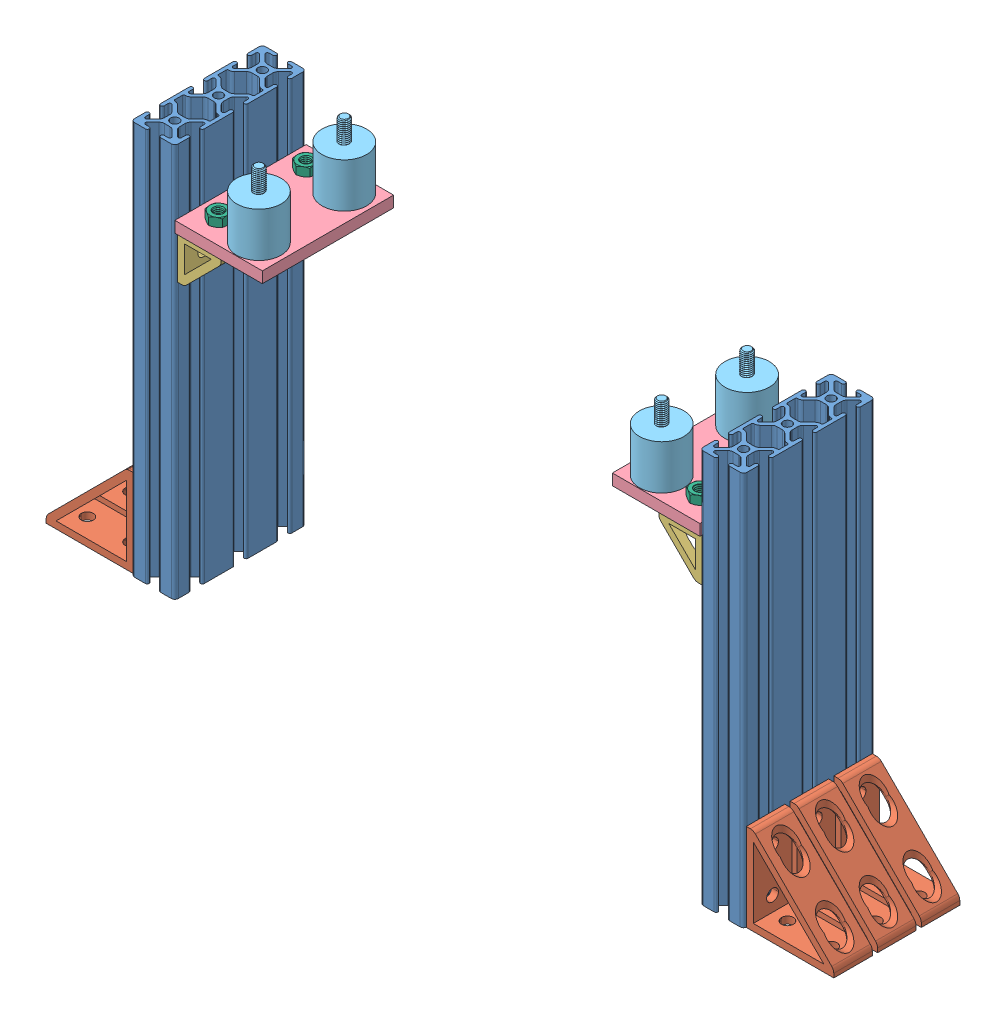
SolidWorks assembly 1, configuration Default. Lengths in mm.
Overall size (450 226.59 75).
32 component instances, 7 part files, 85 mates.
Components (placement in the parent):
- Some Part-2: Some Part [Default] at (-162.5 0 0) x (1 0 0) z (0 -1 0) size (25 75 225)
- Some Part-3: Some Part [Default] at (162.5 0 0) x (1 0 0) z (0 -1 0) size (25 75 225)
- 25_4136-1: 25_4136 [Default] at (-175 0 0) x (0 0 1) z (-1 0 0) size (22 50 50)
- 25_4136-2: 25_4136 [Default] at (175 0 -25) x (0 0 -1) z (1 0 0) size (22 50 50)
- 25_4136-3: 25_4136 [Default] at (175 0 25) x (0 0 -1) z (1 0 0) size (22 50 50)
- 25_4136-4: 25_4136 [Default] at (-175 0 -25) x (0 0 1) z (-1 0 0) size (22 50 50)
- 25_4136-5: 25_4136 [Default] at (175 0 0) x (0 0 -1) z (1 0 0) size (22 50 50)
- 25_4136-6: 25_4136 [Default] at (-175 0 25) x (0 0 1) z (-1 0 0) size (22 50 50)
- 25_4132-1: 25_4132 [Default] at (-150 181.787 25) x (0 0 -1) z (0 -1 0) size (22 25 25)
- 25_4132-2: 25_4132 [Default] at (-150 181.787 -25) x (0 0 -1) z (0 -1 0) size (22 25 25)
- 25_4132-3: 25_4132 [Default] at (-150 181.787 0) x (0 0 1) z (1 0 0) size (22 25 25)
- 25_4132-4: 25_4132 [Default] at (150 181.787 0) x (0 0 -1) z (-1 0 0) size (22 25 25)
- 25_4132-5: 25_4132 [Default] at (150 181.787 25) x (0 0 -1) z (-1 0 0) size (22 25 25)
- 25_4132-6: 25_4132 [Default] at (150 181.787 -25) x (0 0 -1) z (-1 0 0) size (22 25 25)
- Mounting Block-1: Mounting Block [Default] at (-125 188.137 0) x (1 0 0) z (0 -1 0) size (50 75 6.35)
- Mounting Block-2: Mounting Block [Default] at (125 188.137 0) x (-1 0 0) z (0 -1 0) size (50 75 6.35)
- 9225K67_Vibration-Damping Sandwich Mount with Studs-1: 9225K67_Vibration-Damping Sandwich Mount with Studs [9225K67] at (115.071 200.837 -24.4) size (25.4 51.51 25.4)
- 9225K67_Vibration-Damping Sandwich Mount with Studs-2: 9225K67_Vibration-Damping Sandwich Mount with Studs [9225K67] at (-115.071 200.837 24.4) size (25.4 51.51 25.4)
- 9225K67_Vibration-Damping Sandwich Mount with Studs-3: 9225K67_Vibration-Damping Sandwich Mount with Studs [9225K67] at (115.071 200.837 24.4) size (25.4 51.51 25.4)
- 9225K67_Vibration-Damping Sandwich Mount with Studs-4: 9225K67_Vibration-Damping Sandwich Mount with Studs [9225K67] at (-115.071 200.837 -24.4) size (25.4 51.51 25.4)
- 91828A251_18-8 Stainless Steel Hex Nut-1: 91828A251_18-8 Stainless Steel Hex Nut [91828A251] at (115.071 179.287 -24.4) x (1 0 0) z (0 -1 0) size (10 11.55 5.57)
- 94500A314_316 Stainless Steel Button Head Hex Drive Screws-1: 94500A314_316 Stainless Steel Button Head Hex Drive Screws [94500A314] at (137.5 174.487 -25) x (1 0 0) z (0 -1 0) size (10.5 10.5 13.87)
- 91828A251_18-8 Stainless Steel Hex Nut-2: 91828A251_18-8 Stainless Steel Hex Nut [91828A251] at (115.071 179.287 24.4) x (1 0 0) z (0 -1 0) size (10 11.55 5.57)
- 91828A251_18-8 Stainless Steel Hex Nut-3: 91828A251_18-8 Stainless Steel Hex Nut [91828A251] at (-115.071 179.287 -24.4) x (0.837169 0 0.546944) z (0 -1 0) size (10 11.55 5.57)
- 91828A251_18-8 Stainless Steel Hex Nut-4: 91828A251_18-8 Stainless Steel Hex Nut [91828A251] at (137.5 190.637 -25) x (1 0 0) z (0 1 0) size (10 11.55 5.57)
- 91828A251_18-8 Stainless Steel Hex Nut-5: 91828A251_18-8 Stainless Steel Hex Nut [91828A251] at (137.5 190.637 25) x (1 0 0) z (0 -1 0) size (10 11.55 5.57)
- 91828A251_18-8 Stainless Steel Hex Nut-6: 91828A251_18-8 Stainless Steel Hex Nut [91828A251] at (-137.5 190.637 -25) x (1 0 0) z (0 1 0) size (10 11.55 5.57)
- 91828A251_18-8 Stainless Steel Hex Nut-7: 91828A251_18-8 Stainless Steel Hex Nut [91828A251] at (-115.071 179.287 24.4) x (0.837169 0 0.546944) z (0 -1 0) size (10 11.55 5.57)
- 91828A251_18-8 Stainless Steel Hex Nut-8: 91828A251_18-8 Stainless Steel Hex Nut [91828A251] at (-137.5 190.637 25) x (1 0 0) z (0 1 0) size (10 11.55 5.57)
- 94500A314_316 Stainless Steel Button Head Hex Drive Screws-2: 94500A314_316 Stainless Steel Button Head Hex Drive Screws [94500A314] at (137.5 174.487 25) x (1 0 0) z (0 -1 0) size (10.5 10.5 13.87)
- 94500A314_316 Stainless Steel Button Head Hex Drive Screws-3: 94500A314_316 Stainless Steel Button Head Hex Drive Screws [94500A314] at (-137.5 174.487 -25) x (0.731174 0 0.682191) z (0 -1 0) size (10.5 10.5 13.87)
- 94500A314_316 Stainless Steel Button Head Hex Drive Screws-4: 94500A314_316 Stainless Steel Button Head Hex Drive Screws [94500A314] at (-137.5 174.487 25) x (1 0 0) z (0 -1 0) size (10.5 10.5 13.87)
Mates (geometry in assembly coordinates):
- Coincident3: coincident anti-aligned: plane of 1-2 through (-173.93 0 -29.32) normal (0 -1 0)
- Coincident4: coincident anti-aligned: plane of 1-3 through (151.07 0 -29.32) normal (0 -1 0)
- Symmetric1: symmetric aligned: plane of 1-3 through (166.82 0 37.5) normal (0 0 1); plane of 1-3 through (158.18 0 -37.5) normal (0 0 -1)
- Symmetric2: symmetric aligned: plane of 1-2 through (-158.18 0 37.5) normal (0 0 1); plane of 1-2 through (-166.82 0 -37.5) normal (0 0 -1)
- Distance1: distance = 300 mm anti-aligned: plane of 1-2 through (-150 0 20.68) normal (1 0 0); plane of 1-3 through (150 0 -20.68) normal (-1 0 0)
- Distance2: distance = 150 mm aligned: plane of 1-2 through (-150 0 20.68) normal (1 0 0)
- Coincident7: coincident anti-aligned: plane of 1-2 through (-175 0 4.32) normal (-1 0 0); plane of 25_4136-1 through (-175 0 11) normal (1 0 0)
- Coincident8: coincident aligned: plane of 1-2 through (-173.93 0 -29.32) normal (0 -1 0); plane of 25_4136-1 through (-225 0 11) normal (0 -1 0)
- Symmetric3: symmetric aligned: plane of 25_4136-1 through (-221 2.3431 -11) normal (0 0 -1); plane of 25_4136-1 through (-221 2.3431 11) normal (0 0 1)
- Coincident9: coincident anti-aligned: plane of 1-3 through (175 0 -4.32) normal (1 0 0); plane of 25_4136-2 through (175 0 -36) normal (-1 0 0)
- Coincident10: coincident anti-aligned: plane of 1-3 through (175 0 -4.32) normal (1 0 0); plane of 25_4136-3 through (175 0 14) normal (-1 0 0)
- Coincident11: coincident anti-aligned: plane of 1-3 through (175 0 -4.32) normal (1 0 0); plane of 25_4136-5 through (175 0 -11) normal (-1 0 0)
- Coincident12: coincident anti-aligned: plane of 1-2 through (-175 0 -20.68) normal (-1 0 0); plane of 25_4136-4 through (-175 0 -14) normal (1 0 0)
- Coincident13: coincident anti-aligned: plane of 1-2 through (-175 0 4.32) normal (-1 0 0); plane of 25_4136-6 through (-175 0 36) normal (1 0 0)
- Coincident14: coincident aligned: plane of 1-2 through (-173.93 0 -29.32) normal (0 -1 0); plane of 25_4136-6 through (-225 0 36) normal (0 -1 0)
- Coincident15: coincident aligned: plane of 1-2 through (-173.93 0 -29.32) normal (0 -1 0); plane of 25_4136-4 through (-225 0 -14) normal (0 -1 0)
- Coincident17: coincident aligned: plane of 1-3 through (151.07 0 -29.32) normal (0 -1 0); plane of 25_4136-2 through (225 0 -36) normal (0 -1 0)
- Coincident18: coincident aligned: plane of 1-3 through (151.07 0 -29.32) normal (0 -1 0); plane of 25_4136-3 through (225 0 14) normal (0 -1 0)
- Coincident19: coincident aligned: plane of 1-3 through (151.07 0 -29.32) normal (0 -1 0); plane of 25_4136-5 through (225 0 -11) normal (0 -1 0)
- Symmetric4: symmetric aligned: plane of 25_4136-5 through (221 2.3431 11) normal (0 0 1); plane of 25_4136-5 through (221 2.3431 -11) normal (0 0 -1)
- Width1: width: cylinder of 1-3; plane of 25_4136-2 through (164.0737 0 -29.4) normal (0 0 -1); cylinder of 1-3 through (179 37.5 -25) axis (-1 0 0) radius 3.405
- Width2: width: plane of 1-3 through (160.9263 0 29.4) normal (0 0 1); plane of 25_4136-3 through (164.0737 0 20.6) normal (0 0 -1); cylinder of 1-3 through (179 12.5 25) axis (-1 0 0) radius 3.405
- Width3: width: plane of 1-2 through (-160.9263 0 20.6) normal (0 0 -1); plane of 25_4136-6 through (-164.0737 0 29.4) normal (0 0 1); cylinder of 1-2 through (-179 12.5 25) axis (1 0 0) radius 3.405
- Width4: width: plane of 1-2 through (-160.9263 0 -29.4) normal (0 0 -1); plane of 25_4136-4 through (-164.0737 0 -20.6) normal (0 0 1); cylinder of 1-2 through (-179 37.5 -25) axis (1 0 0) radius 3.405
- Coincident20: coincident anti-aligned: plane of 1-2 through (-150 0 20.68) normal (1 0 0); plane of 25_4132-1 through (-150 156.787 14) normal (-1 0 0)
- Parallel1: parallel aligned: plane of 1-2 through (-173.93 225 -29.32) normal (0 1 0); plane of 25_4132-1 through (-150 181.787 14) normal (0 1 0)
- Coincident22: coincident anti-aligned: plane of 1-2 through (-150 0 -4.32) normal (1 0 0); plane of 25_4132-3 through (-150 181.787 11) normal (-1 0 0)
- Parallel2: parallel aligned: plane of 1-2 through (-173.93 225 -29.32) normal (0 1 0); plane of 25_4132-3 through (-125 181.787 11) normal (0 1 0)
- Coincident24: coincident anti-aligned: plane of 1-2 through (-150 0 -29.32) normal (1 0 0); plane of 25_4132-2 through (-150 156.787 -36) normal (-1 0 0)
- Width5: width: plane of 1-2 through (-164.0737 0 29.4) normal (0 0 1); plane of 25_4132-1 through (-160.9263 0 20.6) normal (0 0 -1); cylinder of 1-2 through (-137.5 177.787 25) axis (0 1 0) radius 3.405
- Width6: width: plane of 1-2 through (-164.0737 0 4.4) normal (0 0 1); plane of 25_4132-3 through (-160.9263 0 -4.4) normal (0 0 -1); cylinder of 1-2 through (-137.5 177.787 0) axis (0 1 0) radius 3.405
- Width7: width: plane of 1-2 through (-164.0737 0 -20.6) normal (0 0 1); plane of 25_4132-2 through (-160.9263 0 -29.4) normal (0 0 -1); cylinder of 1-2 through (-137.5 177.787 -25) axis (0 1 0) radius 3.405
- Coincident26: coincident anti-aligned: plane of 1-3 through (150 0 4.32) normal (-1 0 0); plane of 25_4132-6 through (150 181.787 -36) normal (1 0 0)
- Parallel3: parallel aligned: plane of 1-3 through (151.07 225 -29.32) normal (0 1 0); plane of 25_4132-6 through (125 181.787 -36) normal (0 1 0)
- Coincident29: coincident anti-aligned: plane of 1-3 through (150 0 4.32) normal (-1 0 0); plane of 25_4132-5 through (150 181.787 14) normal (1 0 0)
- Parallel4: parallel aligned: plane of 1-3 through (151.07 225 -29.32) normal (0 1 0); plane of 25_4132-5 through (125 181.787 14) normal (0 1 0)
- Coincident31: coincident anti-aligned: plane of 1-3 through (150 0 4.32) normal (-1 0 0); plane of 25_4132-4 through (150 181.787 -11) normal (1 0 0)
- Parallel6: parallel aligned: plane of 1-3 through (151.07 225 -29.32) normal (0 1 0); plane of 25_4132-4 through (125 181.787 -11) normal (0 1 0)
- Width8: width: plane of 1-3 through (164.0737 0 -29.4) normal (0 0 -1); plane of 25_4132-6 through (160.9263 0 -20.6) normal (0 0 1); cylinder of 1-3 through (137.5 177.787 -25) axis (0 1 0) radius 3.405
- Width9: width: plane of 1-3 through (164.0737 0 -4.4) normal (0 0 -1); plane of 25_4132-4 through (160.9263 0 4.4) normal (0 0 1); cylinder of 1-3 through (137.5 177.787 0) axis (0 1 0) radius 3.405
- Width10: width: plane of 1-3 through (164.0737 0 20.6) normal (0 0 -1); plane of 25_4132-5 through (160.9263 0 29.4) normal (0 0 1); cylinder of 1-3 through (137.5 177.787 25) axis (0 1 0) radius 3.405
- Coincident34: coincident anti-aligned: plane of 1-3 through (150 0 -20.68) normal (-1 0 0); plane of Mounting Block-2 through (150 181.787 -37.5) normal (1 0 0)
- Distance3: distance = 36.863 mm aligned: plane of Mounting Block-2 through (125 188.137 0) normal (0 1 0); plane of 1-3 through (151.07 225 -29.32) normal (0 1 0)
- Width11: width: plane of 1-3 through (164.0737 0 -4.4) normal (0 0 -1); plane of Mounting Block-2 through (160.9263 0 4.4) normal (0 0 1); cylinder of 1-3 through (137.5 188.137 0) axis (0 -1 0) radius 3.405
- Coincident36: coincident anti-aligned: plane of 25_4132-6 through (125 181.787 -36) normal (0 1 0); plane of Mounting Block-2 through (125 181.787 0) normal (0 -1 0)
- Coincident37: coincident anti-aligned: plane of 25_4132-4 through (125 181.787 -11) normal (0 1 0); plane of Mounting Block-2 through (125 181.787 0) normal (0 -1 0)
- Coincident38: coincident anti-aligned: plane of 25_4132-5 through (125 181.787 14) normal (0 1 0); plane of Mounting Block-2 through (125 181.787 0) normal (0 -1 0)
- Coincident39: coincident anti-aligned: plane of 1-2 through (-150 0 20.68) normal (1 0 0); plane of Mounting Block-1 through (-150 181.787 37.5) normal (-1 0 0)
- Distance4: distance = 36.863 mm aligned: plane of Mounting Block-1 through (-125 188.137 0) normal (0 1 0); plane of 1-2 through (-173.93 225 -29.32) normal (0 1 0)
- Width12: width: plane of 1-2 through (-160.9263 0 -4.4) normal (0 0 -1); plane of Mounting Block-1 through (-164.0737 0 4.4) normal (0 0 1); cylinder of 1-2 through (-137.5 188.137 0) axis (0 -1 0) radius 3.405
- Coincident41: coincident anti-aligned: plane of 25_4132-1 through (-150 181.787 14) normal (0 1 0); plane of Mounting Block-1 through (-125 181.787 0) normal (0 -1 0)
- Coincident42: coincident anti-aligned: plane of 25_4132-3 through (-125 181.787 11) normal (0 1 0); plane of Mounting Block-1 through (-125 181.787 0) normal (0 -1 0)
- Coincident43: coincident anti-aligned: plane of 25_4132-2 through (-150 181.787 -36) normal (0 1 0); plane of Mounting Block-1 through (-125 181.787 0) normal (0 -1 0)
- Coincident44: coincident anti-aligned: plane of Mounting Block-2 through (125 188.137 0) normal (0 1 0); plane of 9225K67_Vibration-Damping Sandwich Mount with Studs-1 through (102.371 188.137 -24.4) normal (0 -1 0)
- Concentric1: concentric aligned: cylinder of Mounting Block-2 through (115.071 188.137 -24.4) axis (0 -1 0) radius 3.405; circle of 9225K67_Vibration-Damping Sandwich Mount with Studs-1
- Coincident45: coincident anti-aligned: plane of Mounting Block-1 through (-125 188.137 0) normal (0 1 0); plane of 9225K67_Vibration-Damping Sandwich Mount with Studs-4 through (-127.771 188.137 -24.4) normal (0 -1 0)
- Concentric2: concentric aligned: cylinder of Mounting Block-1 through (-115.071 188.137 -24.4) axis (0 -1 0) radius 3.405; circle of 9225K67_Vibration-Damping Sandwich Mount with Studs-4
- Coincident46: coincident anti-aligned: plane of Mounting Block-2 through (125 188.137 0) normal (0 1 0); plane of 9225K67_Vibration-Damping Sandwich Mount with Studs-3 through (102.371 188.137 24.4) normal (0 -1 0)
- Concentric3: concentric aligned: circle of Mounting Block-2; circle of 9225K67_Vibration-Damping Sandwich Mount with Studs-3
- Coincident47: coincident anti-aligned: plane of Mounting Block-1 through (-125 188.137 0) normal (0 1 0); plane of 9225K67_Vibration-Damping Sandwich Mount with Studs-2 through (-127.771 188.137 24.4) normal (0 -1 0)
- Concentric4: concentric aligned: cylinder of Mounting Block-1 through (-115.071 188.137 24.4) axis (0 -1 0) radius 3.405; circle of 9225K67_Vibration-Damping Sandwich Mount with Studs-2
- Coincident48: coincident anti-aligned: plane of Mounting Block-2 through (125 181.787 0) normal (0 -1 0); plane of 91828A251_18-8 Stainless Steel Hex Nut-1 through (110.071 181.787 -21.5132) normal (0 1 0)
- Concentric5: concentric anti-aligned: circle of 9225K67_Vibration-Damping Sandwich Mount with Studs-1; circle of 91828A251_18-8 Stainless Steel Hex Nut-1
- Concentric6: concentric anti-aligned: circle of 9225K67_Vibration-Damping Sandwich Mount with Studs-3; circle of 91828A251_18-8 Stainless Steel Hex Nut-2
- Coincident50: coincident anti-aligned: plane of Mounting Block-2 through (125 181.787 0) normal (0 -1 0); plane of 91828A251_18-8 Stainless Steel Hex Nut-2 through (110.071 181.787 27.2868) normal (0 1 0)
- Coincident51: coincident anti-aligned: plane of Mounting Block-1 through (-125 181.787 0) normal (0 -1 0); plane of 91828A251_18-8 Stainless Steel Hex Nut-3 through (-120.8357 181.787 -24.718) normal (0 1 0)
- Concentric7: concentric aligned: circle of 9225K67_Vibration-Damping Sandwich Mount with Studs-4; circle of 91828A251_18-8 Stainless Steel Hex Nut-3
- Coincident52: coincident anti-aligned: plane of Mounting Block-1 through (-125 181.787 0) normal (0 -1 0); plane of 91828A251_18-8 Stainless Steel Hex Nut-7 through (-120.8357 181.787 24.082) normal (0 1 0)
- Concentric8: concentric aligned: circle of 9225K67_Vibration-Damping Sandwich Mount with Studs-2; circle of 91828A251_18-8 Stainless Steel Hex Nut-7
- Concentric9: concentric anti-aligned: cylinder of Mounting Block-1 through (-137.5 188.137 -25) axis (0 -1 0) radius 3.405; circle of 94500A314_316 Stainless Steel Button Head Hex Drive Screws-3
- Coincident54: coincident anti-aligned: plane of 25_4132-2 through (-146 177.787 -36) normal (0 -1 0); plane of 94500A314_316 Stainless Steel Button Head Hex Drive Screws-3 through (-137.7645 177.787 -32.427) normal (0 1 0)
- Coincident55: coincident anti-aligned: plane of Mounting Block-1 through (-125 188.137 0) normal (0 1 0); plane of 91828A251_18-8 Stainless Steel Hex Nut-6 through (-142.5 188.137 -27.8868) normal (0 -1 0)
- Concentric10: concentric aligned: circle of Mounting Block-1; circle of 91828A251_18-8 Stainless Steel Hex Nut-6
- Coincident56: coincident anti-aligned: plane of Mounting Block-1 through (-125 188.137 0) normal (0 1 0); plane of 91828A251_18-8 Stainless Steel Hex Nut-8 through (-142.5 188.137 22.1132) normal (0 -1 0)
- Concentric11: concentric aligned: circle of Mounting Block-1; circle of 91828A251_18-8 Stainless Steel Hex Nut-8
- Coincident57: coincident anti-aligned: plane of Mounting Block-2 through (125 188.137 0) normal (0 1 0); plane of 91828A251_18-8 Stainless Steel Hex Nut-4 through (132.5 188.137 -27.8868) normal (0 -1 0)
- Concentric12: concentric aligned: circle of Mounting Block-2; circle of 91828A251_18-8 Stainless Steel Hex Nut-4
- Coincident58: coincident anti-aligned: plane of 25_4132-6 through (130.6569 177.787 -36) normal (0 -1 0); plane of 94500A314_316 Stainless Steel Button Head Hex Drive Screws-1 through (132.24 177.787 -30.25) normal (0 1 0)
- Concentric13: concentric aligned: cylinder of 25_4132-6 through (137.5 177.787 -25) axis (0 1 0) radius 3.405; circle of 94500A314_316 Stainless Steel Button Head Hex Drive Screws-1
- Coincident59: coincident anti-aligned: plane of 25_4132-1 through (-146 177.787 14) normal (0 -1 0); plane of 94500A314_316 Stainless Steel Button Head Hex Drive Screws-4 through (-142.76 177.787 19.75) normal (0 1 0)
- Concentric14: concentric aligned: cylinder of 25_4132-1 through (-137.5 177.787 25) axis (0 1 0) radius 3.405; circle of 94500A314_316 Stainless Steel Button Head Hex Drive Screws-4
- Coincident60: coincident anti-aligned: plane of 25_4132-5 through (130.6569 177.787 14) normal (0 -1 0); plane of 94500A314_316 Stainless Steel Button Head Hex Drive Screws-2 through (132.24 177.787 19.75) normal (0 1 0)
- Concentric15: concentric anti-aligned: cylinder of Mounting Block-2 through (137.5 188.137 25) axis (0 -1 0) radius 3.405; circle of 94500A314_316 Stainless Steel Button Head Hex Drive Screws-2
- Coincident61: coincident anti-aligned: plane of Mounting Block-2 through (125 188.137 0) normal (0 1 0); plane of 91828A251_18-8 Stainless Steel Hex Nut-5 through (132.5 188.137 27.8868) normal (0 -1 0)
- Concentric16: concentric anti-aligned: cylinder of Mounting Block-2 through (137.5 188.137 25) axis (0 -1 0) radius 3.405; circle of 91828A251_18-8 Stainless Steel Hex Nut-5
